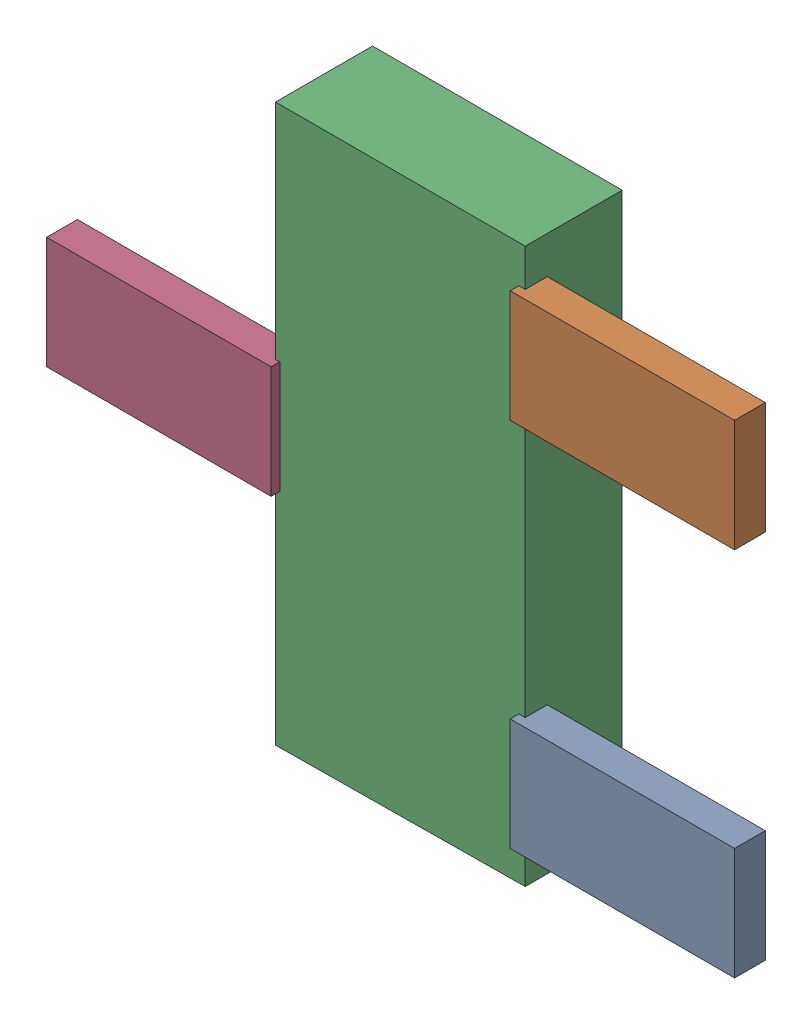
SolidWorks assembly Q3, configuration Default. Lengths in mm.
Overall size (3.58 2.9 0.55).
8 component instances, 2 part files, 0 mates.
Components (placement in the parent):
- 432134544-1: 432134544 [Default] at (19.8508 22.0323 -0.5715) size (1.17 0.58 0.16)
  - Extruded (38)-1: Extruded (38) [Default] at origin size (1.17 0.58 0.16)
- 432134544_1-1: 432134544_1 [Default] at (19.8508 23.9627 -0.5715) size (1.17 0.58 0.16)
  - Extruded (38)-1: Extruded (38) [Default] at origin size (1.17 0.58 0.16)
- 710423824-1: 710423824 [Default] at (18.65 23 -0.9615) size (1.3 2.9 0.5)
  - Extruded (39)-1: Extruded (39) [Default] at origin size (1.3 2.9 0.5)
- 432134544_2-1: 432134544_2 [Default] at (17.4378 22.9975 -0.5715) size (1.17 0.58 0.16)
  - Extruded (38)-1: Extruded (38) [Default] at origin size (1.17 0.58 0.16)
